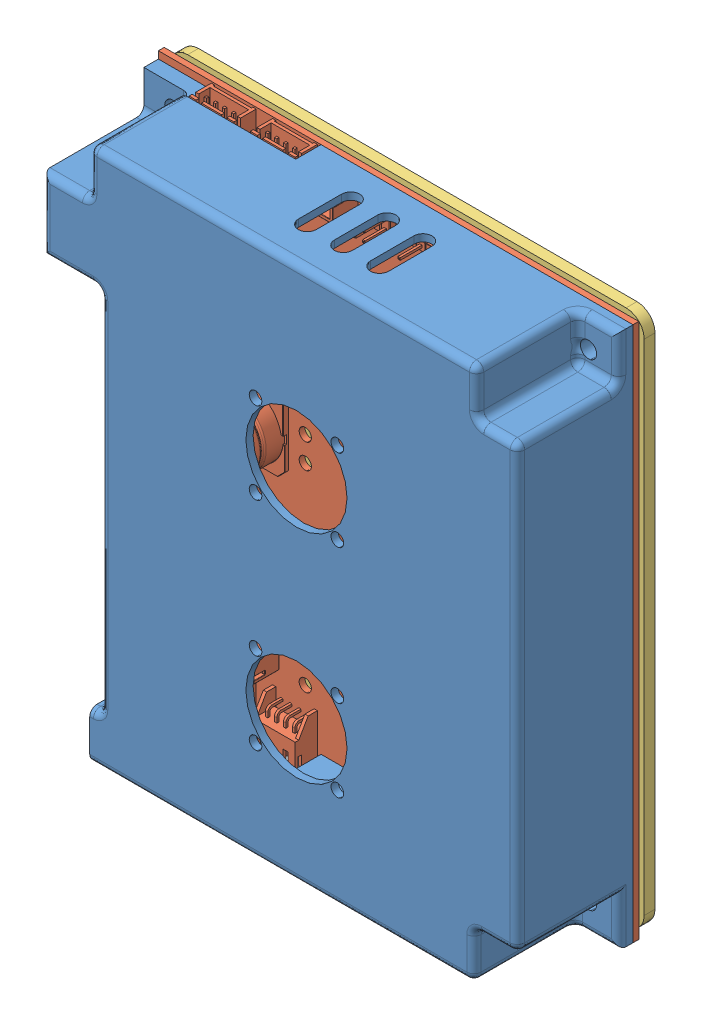
SolidWorks assembly Motor controller enclosure, configuration Default. Lengths in mm.
Overall size (131.32 148.08 38.1).
3 component instances, 3 part files, 3 mates.
Components (placement in the parent):
- Motor controller enclosure-1: Motor controller enclosure [Default] at (6.0318 -15.6118 25.7238) x (0 1 0) z (1 0 0) size (148.08 32 131.32)
- MotorCont PCB-2: MotorCont PCB [Default] at (-56.1669 -89.6118 -4.2762) size (131.32 148.08 22.7)
- Motor controller bottom plate-1: Motor controller bottom plate [Default] at (9.8991 -15.3673 -10.3716) x (-1 0 0) z (0 1 0) size (131.32 3 148.08)
Mates (geometry in assembly coordinates):
- Coincident1: coincident aligned: plane of Motor controller enclosure-1 through (-56.1669 -89.6118 -0.2762) normal (-1 0 0); plane of MotorCont PCB-2 through (-56.1669 58.4702 -5.8716) normal (-1 0 0)
- Coincident2: coincident aligned: plane of Motor controller enclosure-1 through (-43.1669 -89.6118 -0.2762) normal (0 -1 0); plane of MotorCont PCB-2 through (-56.1669 -89.6118 -5.8716) normal (0 -1 0)
- Coincident3: coincident anti-aligned: plane of Motor controller enclosure-1 through (6.0318 -15.6118 -4.2762) normal (0 0 -1); plane of MotorCont PCB-2 through (9.4921 -15.5708 -4.2762) normal (0 0 1)
